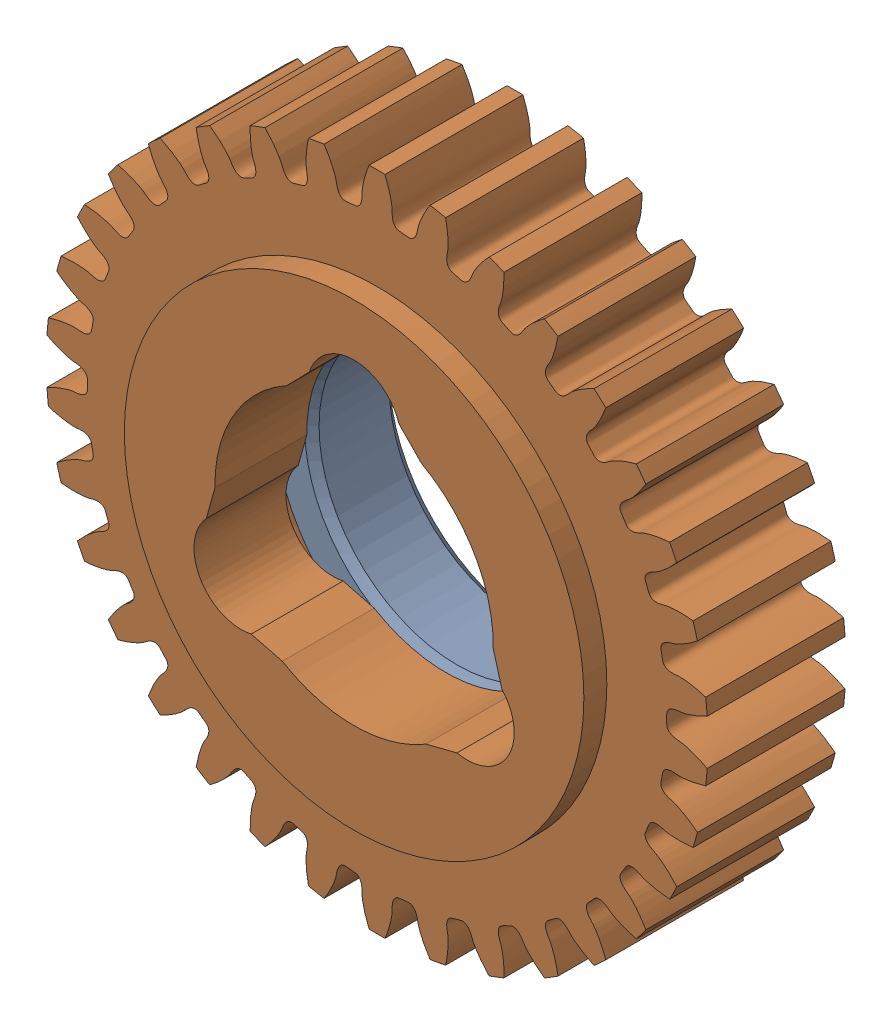
SolidWorks assembly 217-3212-101 Rev1, configuration Default. Lengths in mm.
Overall size (46.46 46.56 12.7).
2 component instances, 2 part files, 0 mates.
Components (placement in the parent):
- 217-2428-022 Rev1-1: 217-2428-022 Rev1 [Default] at (6.7035 14.0527 24.6087) size (28.57 28.57 6.1)
- 217-3212-001 Rev1_34t-1: 217-3212-001 Rev1_34t [Default] at (6.7035 14.0527 27.9107) size (46.46 46.56 11.11)
